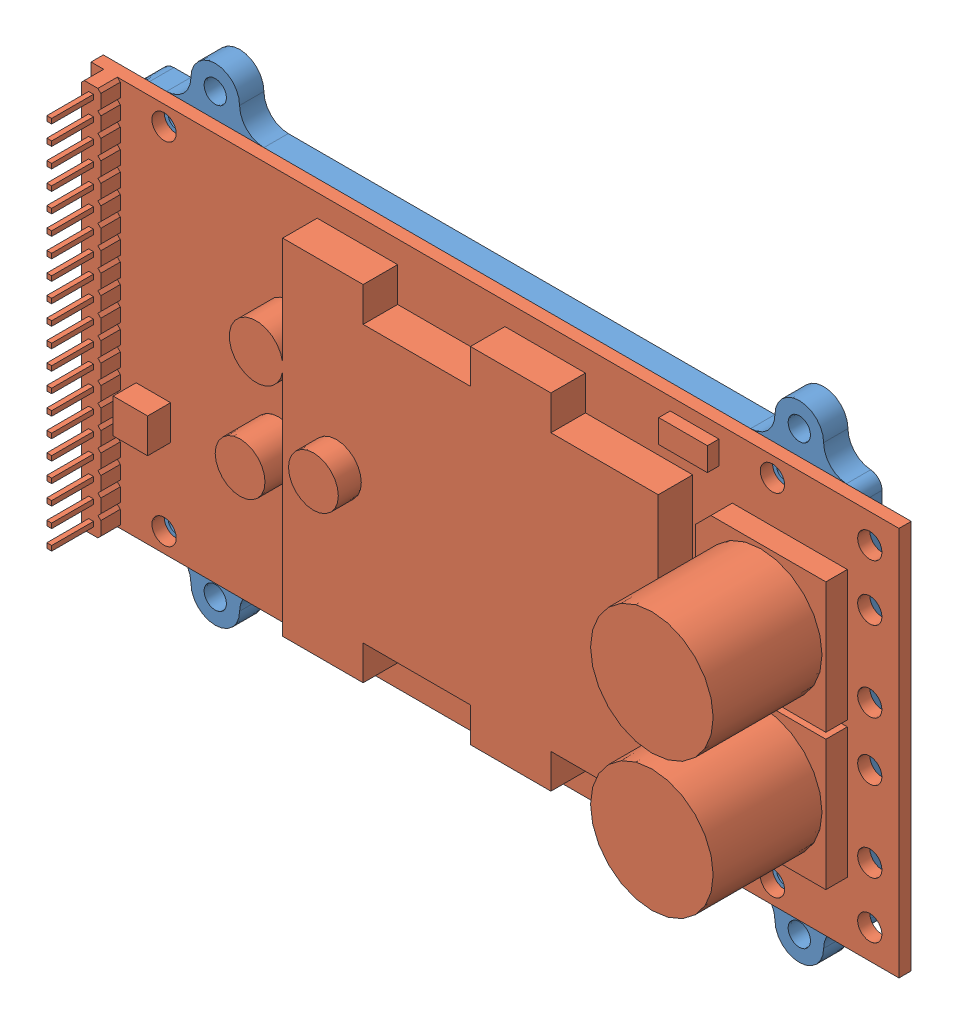
SolidWorks assembly ragebridge2 lpm assembly, configuration Default. Lengths in mm.
Overall size (105.41 63.5 21.77).
2 component instances, 2 part files, 0 mates.
Components (placement in the parent):
- heatsink 0002-1: heatsink 0002 [Default] at origin size (93.98 63.5 3.17)
- ragebridge2 lpm-1: ragebridge2 lpm [Default] at (52.705 25.4 3.175) x (1 0 0) z (0 -1 0) size (105.41 18.6 50.8)
